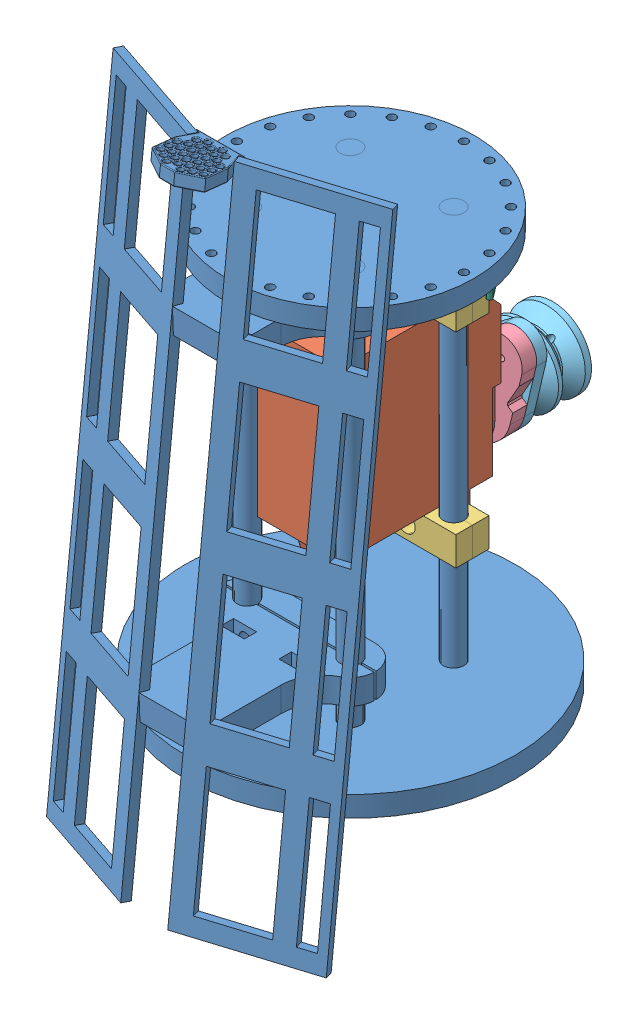
SolidWorks assembly Assem_servo_mount, configuration Default. Lengths in mm.
Overall size (80 155.5 98.93).
10 component instances, 6 part files, 24 mates.
Components (placement in the parent):
- sense_mount v4-1: sense_mount v4 [Default] at origin size (80 155.5 89.93)
- Servo-1: Servo [Default] at (0 51.75 12.5) x (0 -1 0) z (1 0 0) size (54.75 43 19.9)
- Servo_mount-1: Servo_mount [Default] at (0 23.5 -8.5) size (34.1 7 4)
- Servo_mount-2: Servo_mount [Default] at (0 73 -8.5) size (34.1 7 4)
- Servo_mount-3: Servo_mount [Default] at (0 73 -16.5) x (-1 0 0) z (0 0 -1) size (34.1 7 4)
- Servo_mount-4: Servo_mount [Default] at (0 23.5 -16.5) x (-1 0 0) z (0 0 -1) size (34.1 7 4)
- Pulley_servo_adapter-1: Pulley_servo_adapter [Default] at (0 41.25 -33) x (-0.54741 -0.836864 0) z (-0.836864 0.54741 0) size (36 6.5 18.8)
- Pulley-1: Pulley [Default] at (0 41.25 -41.5) x (0 0 1) z (-0.836864 0.54741 0) size (16 36 18.8)
- Spacer10-1: Spacer10 [Default] at (-12.5 80 -12.5) x (0.325774 0 0.945448) z (-0.945448 0 0.325774) size (11.2 10 9.65)
- Spacer10-2: Spacer10 [Default] at (12.5 80 -12.5) x (-0.604031 0 -0.796961) z (0.796961 0 -0.604031) size (11.2 10 9.65)
Mates (geometry in assembly coordinates):
- Coincident1: coincident: plane of Servo_mount-1 through (0 30.5 -12.5) normal (0 0 -1); plane of Servo_mount-4 through (0 30.5 -12.5) normal (0 0 1)
- Concentric1: concentric: cylinder of Servo_mount-1 through (12.5 30.5 -12.5) axis (0 -1 0) radius 2.55; cylinder of Servo_mount-4 through (12.5 30.5 -12.5) axis (0 -1 0) radius 2.55
- Coincident2: coincident: plane of Servo_mount-1 through (-12.5 30.5 -12.5) normal (0 1 0); plane of Servo_mount-4 through (12.5 30.5 -12.5) normal (0 1 0)
- Coincident3: coincident: plane of Servo_mount-2 through (0 80 -12.5) normal (0 0 -1); plane of Servo_mount-3 through (0 80 -12.5) normal (0 0 1)
- Concentric2: concentric: cylinder of Servo_mount-2 through (12.5 80 -12.5) axis (0 -1 0) radius 2.55; cylinder of Servo_mount-3 through (12.5 80 -12.5) axis (0 -1 0) radius 2.55
- Coincident4: coincident: plane of Servo_mount-2 through (-12.5 80 -12.5) normal (0 1 0); plane of Servo_mount-3 through (12.5 80 -12.5) normal (0 1 0)
- Concentric3: concentric: cylinder of Servo-1 through (5 76.5 -10.0618) axis (0 0 -1) radius 2.2; cylinder of Servo_mount-3 through (5 76.5 -6.2775) axis (0 0 -1) radius 2.2
- Coincident5: coincident: plane of Servo-1 through (0 51.75 -16.5) normal (0 0 1); plane of Servo_mount-3 through (0 80 -16.5) normal (0 0 -1)
- Coincident6: coincident: plane of Servo-1 through (0 51.75 -16.5) normal (0 0 1); plane of Servo_mount-4 through (0 30.5 -16.5) normal (0 0 -1)
- Concentric4: concentric: cylinder of Servo-1 through (-5 27 -10.0618) axis (0 0 -1) radius 2.2; cylinder of Servo_mount-1 through (-5 27 -18.7225) axis (0 0 1) radius 2.2
- Concentric5: concentric: cylinder of sense_mount v4-1 through (12.5 0 -12.5) axis (0 1 0) radius 2.5; cylinder of Servo_mount-2 through (12.5 80 -12.5) axis (0 -1 0) radius 2.55
- Concentric6: concentric: cylinder of sense_mount v4-1 through (-12.5 0 -12.5) axis (0 1 0) radius 2.5; cylinder of Servo_mount-2 through (-12.5 80 -12.5) axis (0 -1 0) radius 2.55
- Concentric7: concentric: cylinder of Servo-1 through (-5 76.5 -10.0618) axis (0 0 -1) radius 2.2; cylinder of Servo_mount-3 through (-5 76.5 -6.2775) axis (0 0 -1) radius 2.2
- Concentric8: concentric: cylinder of Servo-1 through (5 27 -10.0618) axis (0 0 -1) radius 2.2; cylinder of Servo_mount-4 through (5 27 -6.2775) axis (0 0 -1) radius 2.2
- Concentric9: concentric: cylinder of Servo-1 through (0 41.25 -30.5) axis (0 0 1) radius 3; cylinder of Pulley_servo_adapter-1 through (0 41.25 -26.5) axis (0 0 -1) radius 3
- Coincident7: coincident: plane of Servo-1 through (0 41.25 -30.5) normal (0 0 -1); plane of Pulley_servo_adapter-1 through (0 41.25 -30.5) normal (0 0 1)
- Coincident8: coincident: plane of Pulley_servo_adapter-1 through (0 41.25 -33) normal (0 0 -1); plane of Pulley-1 through (-7.1163 30.3708 -33) normal (0 0 1)
- Concentric10: concentric: cylinder of Pulley_servo_adapter-1 through (7.1163 52.1292 -26.5) axis (0 0 -1) radius 0.75; cylinder of Pulley-1 through (7.1163 52.1292 -33) axis (0 0 -1) radius 1
- Concentric11: concentric: cylinder of Pulley_servo_adapter-1 through (-7.1163 30.3708 -26.5) axis (0 0 -1) radius 0.75; cylinder of Pulley-1 through (-7.1163 30.3708 -33) axis (0 0 -1) radius 1
- Concentric12: concentric: cylinder of sense_mount v4-1 through (12.5 0 -12.5) axis (0 1 0) radius 2.5; cylinder of Spacer10-2 through (12.5 90 -12.5) axis (0 -1 0) radius 2.5
- Concentric13: concentric: cylinder of sense_mount v4-1 through (-12.5 0 -12.5) axis (0 1 0) radius 2.5; cylinder of Spacer10-1 through (-12.5 90 -12.5) axis (0 -1 0) radius 2.5
- Coincident9: coincident: plane of sense_mount v4-1 through (0 90 0) normal (0 -1 0); plane of Spacer10-2 through (12.5 90 -12.5) normal (0 1 0)
- Coincident10: coincident: plane of sense_mount v4-1 through (0 90 0) normal (0 -1 0); plane of Spacer10-1 through (-12.5 90 -12.5) normal (0 1 0)
- Coincident11: coincident: plane of Servo_mount-2 through (-12.5 80 -12.5) normal (0 1 0); plane of Spacer10-2 through (12.5 80 -12.5) normal (0 -1 0)
